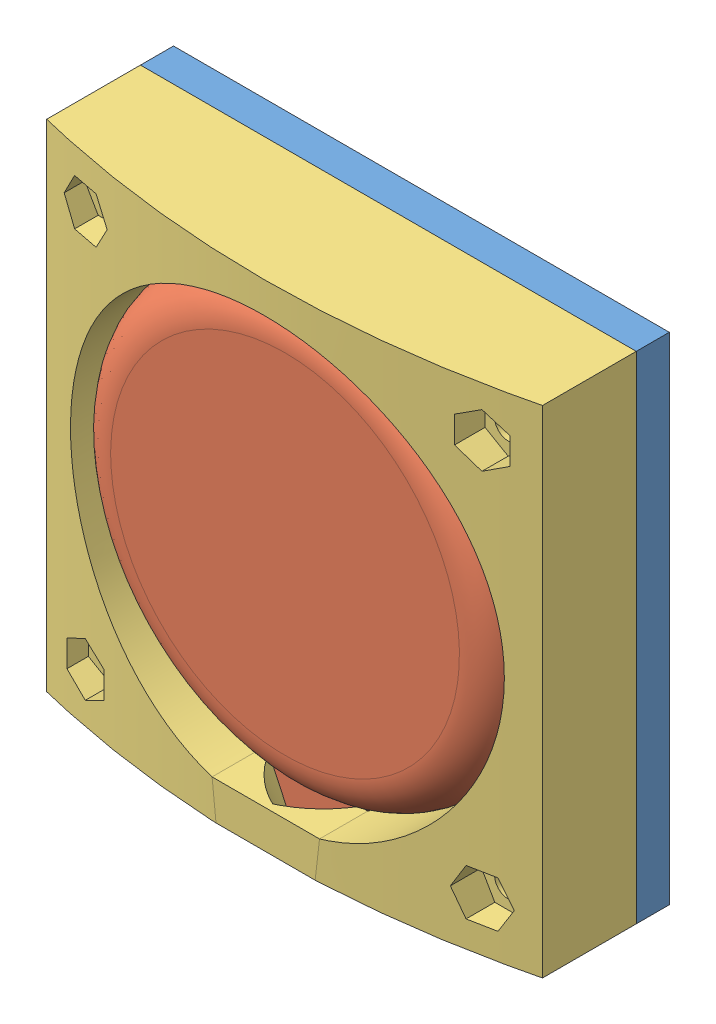
SolidWorks assembly GNSS_antenna, configuration 預設. Lengths in mm.
Overall size (60 60.66 19.01).
3 component instances, 3 part files, 5 mates.
Components (placement in the parent):
- GNSS_antenna_socket_cap-1: GNSS_antenna_socket_cap [預設] at origin size (60 60 4)
- GPSR_antenna-1: GPSR_antenna [預設] at (0 0 3) x (-0.025681 0.99967 0) z (0.99967 0.025681 0) size (56.1 13.5 52.2)
- GNSS_antenna_socket-1: GNSS_antenna_socket [預設] at (0 30 11.5) x (1 0 0) z (0 -1 0) size (60 15.01 60.02)
Mates (geometry in assembly coordinates):
- 同軸心1: concentric aligned: circle of GNSS_antenna_socket_cap-1; circle of GPSR_antenna-1
- 重合/共線/共點2: coincident anti-aligned: plane of GNSS_antenna_socket_cap-1 through (0 0 3) normal (0 0 1); plane of GPSR_antenna-1 through (-0.6703 26.0914 3) normal (0 0 -1)
- 同軸心2: concentric anti-aligned: cylinder of GNSS_antenna_socket_cap-1 through (24 -24 0) axis (0 0 1) radius 1.65; cylinder of GNSS_antenna_socket-1 through (24 -24 19) axis (0 0 -1) radius 1.65
- 同軸心3: concentric aligned: circle of GNSS_antenna_socket_cap-1; cylinder of GNSS_antenna_socket-1 through (-24 -24 19) axis (0 0 -1) radius 1.65
- 重合/共線/共點4: coincident anti-aligned: plane of GNSS_antenna_socket_cap-1 through (0 0 4) normal (0 0 1); plane of GNSS_antenna_socket-1 through (-30 30 4) normal (0 0 -1)
